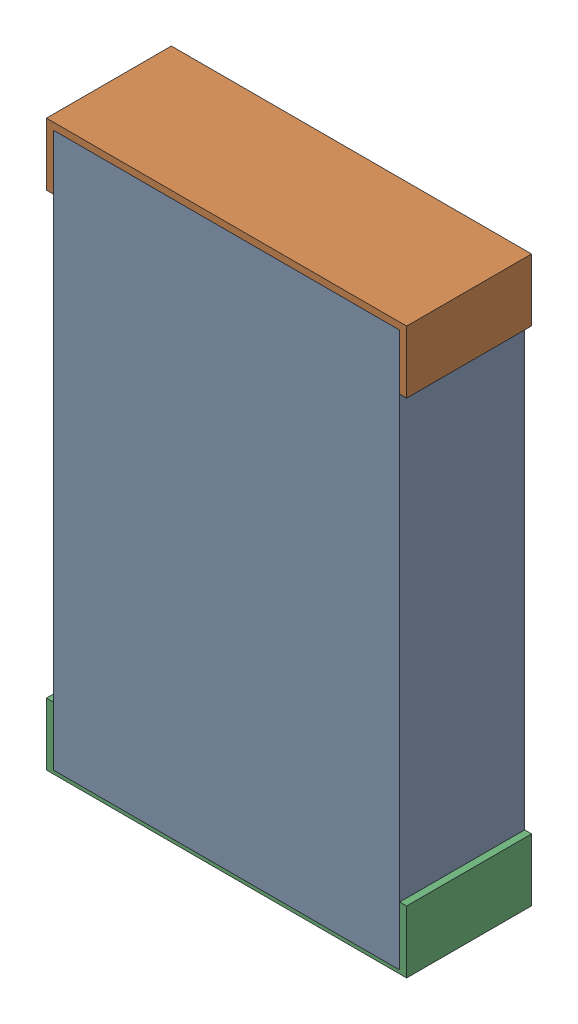
SolidWorks assembly C23, configuration Default. Lengths in mm.
Overall size (1.3 2.04 0.45).
6 component instances, 2 part files, 0 mates.
Components (placement in the parent):
- 740904480-1: 740904480 [Default] at (78.486 26.162 -2.0506) size (1.25 2 0.45)
  - Extruded_34-1: Extruded_34 [Default] at origin size (1.25 2 0.45)
- 740902240-1: 740902240 [Default] at (78.486 27.0745 -2.0516) size (1.3 0.23 0.45)
  - Extruded_35-1: Extruded_35 [Default] at origin size (1.3 0.23 0.45)
- 740902240-2: 740902240 [Default] at (78.486 25.262 -2.0516) size (1.3 0.23 0.45)
  - Extruded_35-1: Extruded_35 [Default] at origin size (1.3 0.23 0.45)
